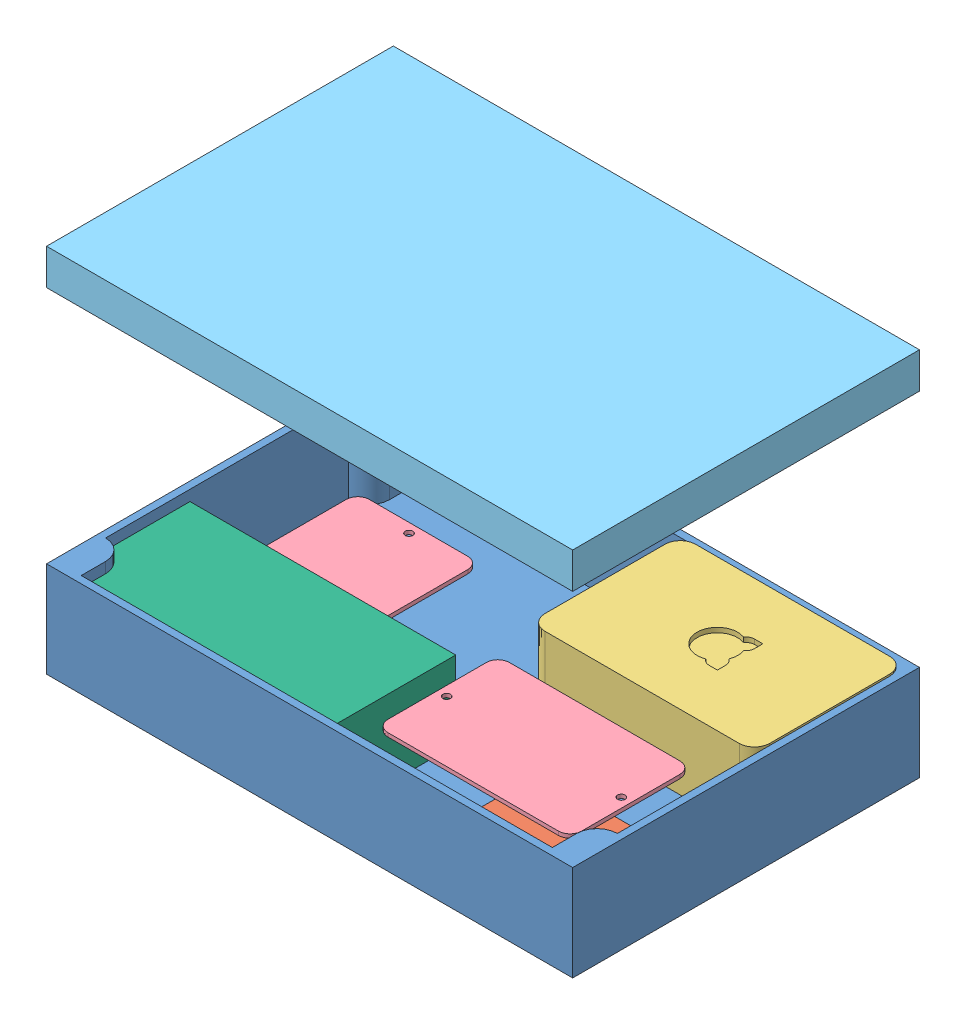
SolidWorks assembly PICase_Assembly_v4, configuration Default. Lengths in mm.
Overall size (220 155 145).
7 component instances, 6 part files, 22 mates.
Components (placement in the parent):
- PICase220x145x55_v1-1: PICase220x145x55_v1 [Default] at (-152.1826 -9.2207 87.4359) size (220 40 145)
- 12Vto5VMicroUsb_v1-1: 12Vto5VMicroUsb_v1 [Default] at (27.1126 -5.9238 53.4522) size (63 14 42)
- RaspberryPi3B_v1-1: RaspberryPi3B_v1 [Default] at (-29.1826 0.5457 8.4359) size (94 31 65.5)
- ProtoBoard_v1-1: ProtoBoard_v1 [Default] at (48.4251 21.1338 18.3498) x (-1 0 0) z (0 0 -1) size (80.96 1.59 50.8)
- ProtoBoard_v1-2: ProtoBoard_v1 [Default] at (-67.94 23.2762 71.7073) x (0 0 -1) z (1 0 0) size (80.96 1.59 50.8)
- PICase_LID_220x145x55_v1-1: PICase_LID_220x145x55_v1 [Default] at (-152.1826 145.7793 -57.5641) x (1 0 0) z (0 0 -1) size (220 15 145)
- PowerSupply_v2-1: PowerSupply_v2 [Default] at (-149.1826 -6.2207 84.4359) size (138.11 32.54 53.98)
Mates (geometry in assembly coordinates):
- Parallel1: parallel anti-aligned: plane of PICase220x145x55_v1-1 through (-152.1826 -6.2207 87.4359) normal (0 1 0); plane of RaspberryPi3B_v1-1 through (-29.1826 0.5457 8.4359) normal (0 -1 0)
- Parallel2: parallel anti-aligned: plane of PICase220x145x55_v1-1 through (-152.1826 -6.2207 87.4359) normal (0 1 0); plane of ProtoBoard_v1-1 through (48.4251 21.1338 18.3498) normal (0 -1 0)
- Parallel4: parallel anti-aligned: plane of PICase220x145x55_v1-1 through (-152.1826 -9.2207 87.4359) normal (0 -1 0); plane of PICase_LID_220x145x55_v1-1 through (-152.1826 145.7793 -57.5641) normal (0 1 0)
- Coincident6: coincident aligned: plane of PICase220x145x55_v1-1 through (-152.1826 -6.2207 87.4359) normal (-1 0 0); plane of PICase_LID_220x145x55_v1-1 through (-152.1826 142.7793 -57.5641) normal (-1 0 0)
- Coincident9: coincident aligned: plane of PICase220x145x55_v1-1 through (-152.1826 -6.2207 87.4359) normal (0 0 1); plane of PICase_LID_220x145x55_v1-1 through (-152.1826 142.7793 87.4359) normal (0 0 1)
- LimitDistance1: limit distance = 100 mm anti-aligned: plane of PICase220x145x55_v1-1 through (-152.1826 30.7793 87.4359) normal (0 1 0); plane of PICase_LID_220x145x55_v1-1 through (-152.1826 130.7793 -57.5641) normal (0 -1 0)
- LimitDistance2: limit distance = 6.7664 mm anti-aligned: plane of RaspberryPi3B_v1-1 through (-29.1826 0.5457 8.4359) normal (0 -1 0); plane of PICase220x145x55_v1-1 through (-152.1826 -6.2207 87.4359) normal (0 1 0)
- LimitDistance4: limit distance = 120 mm anti-aligned: plane of RaspberryPi3B_v1-1 through (-29.1826 31.5457 8.4359) normal (-1 0 0); plane of PICase220x145x55_v1-1 through (-149.1826 334.2655 -35.8641) normal (1 0 0)
- LimitDistance6: limit distance = 76 mm anti-aligned: plane of PICase220x145x55_v1-1 through (-140.6826 334.2655 84.4359) normal (0 0 -1); plane of RaspberryPi3B_v1-1 through (-29.1826 31.5457 8.4359) normal (0 0 1)
- LimitDistance5: limit distance = 6.7664 mm anti-aligned: plane of RaspberryPi3B_v1-1 through (-29.1826 0.5457 8.4359) normal (0 -1 0); plane of PICase220x145x55_v1-1 through (-152.1826 -6.2207 87.4359) normal (0 1 0)
- Parallel5: parallel anti-aligned: plane of PICase220x145x55_v1-1 through (-152.1826 -6.2207 87.4359) normal (0 1 0); plane of PowerSupply_v2-1 through (-149.1826 -6.2207 84.4359) normal (0 -1 0)
- Parallel6: parallel aligned: plane of PICase220x145x55_v1-1 through (-152.1826 -6.2207 87.4359) normal (0 0 1); plane of PowerSupply_v2-1 through (-149.1826 26.323 84.4359) normal (0 0 1)
- Parallel7: parallel aligned: plane of PICase220x145x55_v1-1 through (-152.1826 -6.2207 87.4359) normal (-1 0 0); plane of PowerSupply_v2-1 through (-149.1826 26.323 84.4359) normal (-1 0 0)
- LimitDistance7: limit distance = 0 mm anti-aligned: plane of PowerSupply_v2-1 through (-149.1826 26.323 84.4359) normal (-1 0 0); plane of PICase220x145x55_v1-1 through (-149.1826 334.2655 -35.8641) normal (1 0 0)
- LimitDistance8: limit distance = 0 mm anti-aligned: plane of PowerSupply_v2-1 through (-149.1826 26.323 84.4359) normal (0 0 1); plane of PICase220x145x55_v1-1 through (-140.6826 334.2655 84.4359) normal (0 0 -1)
- LimitDistance9: limit distance = 0 mm anti-aligned: plane of PowerSupply_v2-1 through (-149.1826 -6.2207 84.4359) normal (0 -1 0); plane of PICase220x145x55_v1-1 through (-152.1826 -6.2207 87.4359) normal (0 1 0)
- LimitDistance10: limit distance = 27.3545 mm anti-aligned: plane of ProtoBoard_v1-1 through (48.4251 21.1338 18.3498) normal (0 -1 0); plane of PICase220x145x55_v1-1 through (-152.1826 -6.2207 87.4359) normal (0 1 0)
- LimitDistance11: limit distance = 116.6451 mm anti-aligned: plane of PICase220x145x55_v1-1 through (-149.1826 334.2655 -35.8641) normal (1 0 0); plane of ProtoBoard_v1-1 through (-32.5374 22.7213 18.3498) normal (-1 0 0)
- LimitDistance12: limit distance = 15.2861 mm anti-aligned: plane of PICase220x145x55_v1-1 through (-140.6826 334.2655 84.4359) normal (0 0 -1); plane of ProtoBoard_v1-1 through (48.4251 22.7213 69.1498) normal (0 0 1)
- LimitDistance13: limit distance = 12.7286 mm anti-aligned: plane of PICase220x145x55_v1-1 through (-140.6826 334.2655 84.4359) normal (0 0 -1); plane of ProtoBoard_v1-2 through (-67.94 24.8637 71.7073) normal (0 0 1)
- LimitDistance14: limit distance = 29.4969 mm anti-aligned: plane of PICase220x145x55_v1-1 through (-152.1826 -6.2207 87.4359) normal (0 1 0); plane of ProtoBoard_v1-2 through (-67.94 23.2762 71.7073) normal (0 -1 0)
- LimitDistance15: limit distance = 30.4426 mm anti-aligned: plane of PICase220x145x55_v1-1 through (-149.1826 334.2655 -35.8641) normal (1 0 0); plane of ProtoBoard_v1-2 through (-118.74 24.8637 71.7073) normal (-1 0 0)
